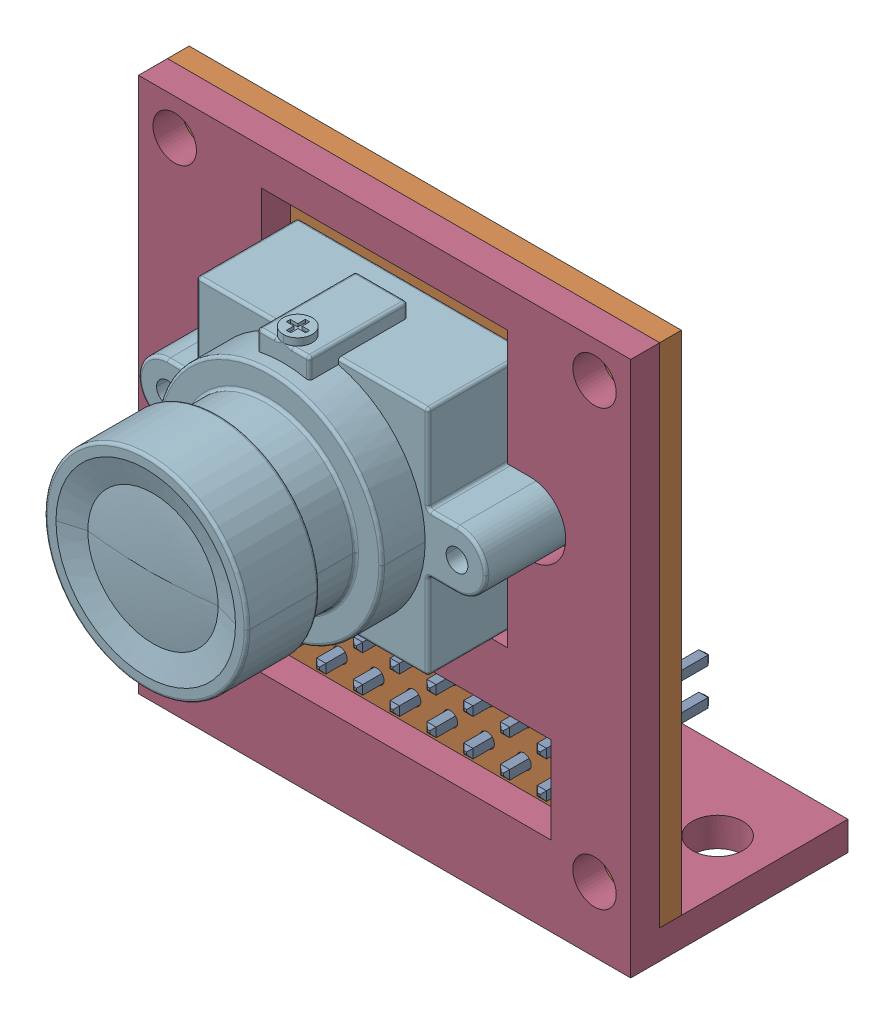
SolidWorks assembly support_camera + camera, configuration Valor predeterminado. Lengths in mm.
Overall size (34 37 31.5).
2 component instances, 2 part files, 3 mates.
Components (placement in the parent):
- components_camera_ov7670-1: components_camera_ov7670 [Valor predeterminado] at (-265.1441 2.2232 -5.7) size (34 35 28.6)
- support_camera-1: support_camera [Valor predeterminado] at (-259.8338 5.3939 -4.2) size (34 37 15)
Mates (geometry in assembly coordinates):
- Coincidente1: coincident anti-aligned: plane of Camera OV7670-1 through (-265.1441 2.2232 -4.2) normal (0 0 1); plane of suporte camera-1 through (-259.8338 5.3939 -4.2) normal (0 0 -1)
- Concêntrico1: concentric aligned: cylinder of Camera OV7670-1 through (-250.6441 -12.7768 -4.2) axis (0 0 -1) radius 1.5; cylinder of suporte camera-1 through (-250.6441 -12.7768 -2.2) axis (0 0 -1) radius 1.5
- Concêntrico2: concentric aligned: cylinder of Camera OV7670-1 through (-279.6441 17.2232 -4.2) axis (0 0 -1) radius 1.5; cylinder of suporte camera-1 through (-279.6441 17.2232 -2.2) axis (0 0 -1) radius 1.5
